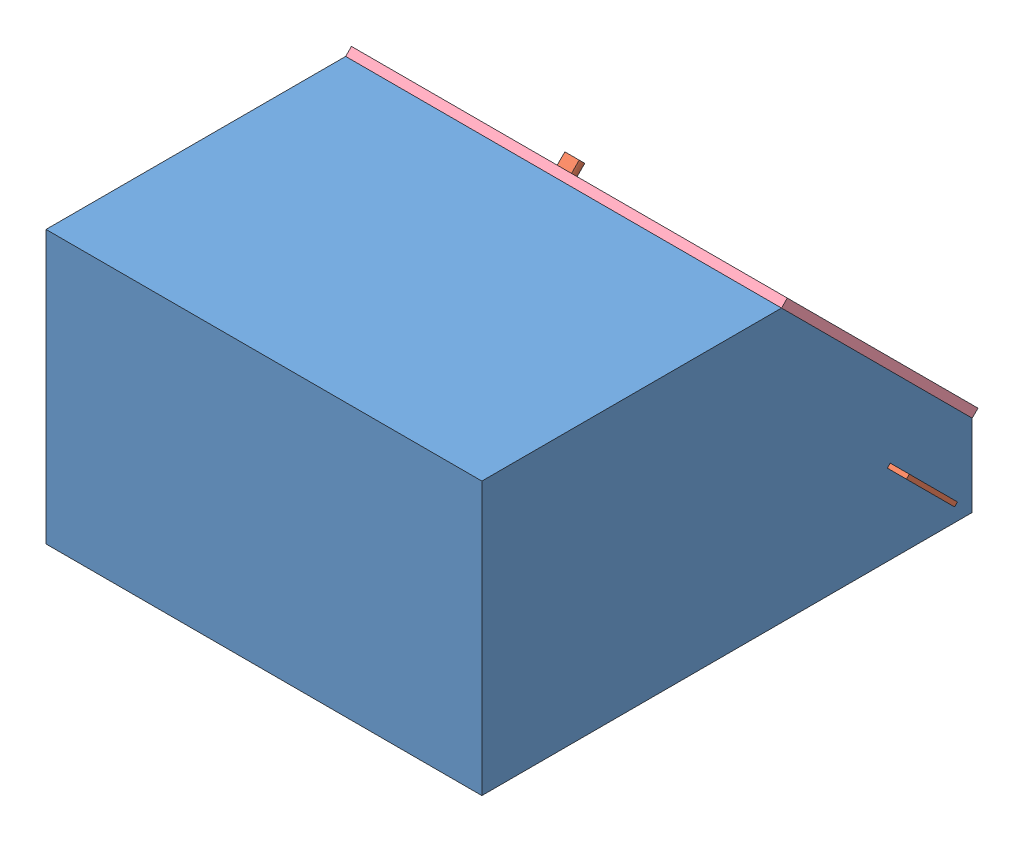
SolidWorks assembly Electronics Box, configuration Default. Lengths in mm.
Overall size (167 103.37 199.93).
8 component instances, 7 part files, 16 mates.
Components (placement in the parent):
- Enclosure Base-1: Enclosure Base [Default] at (0 103 -802.3521) x (0 0 1) z (1 0 0) size (180 100 160)
- lcd-1: lcd [Default] at (-153 49.1312 -757.9367) x (1 0 0) z (0 0.707107 0.707107) size (160 30 64)
- Makerbase-1: Makerbase [Default] at (-100 94.4 -667.3521) x (1 0 0) z (0 0 -1) size (110 22.06 84)
- PC FAN-1: PC FAN [Default] at (-64 15.5 -695.3521) x (-1 0 0) z (0 1 0) size (183.81 183.8 33.39) (hidden)
  - CPU Fan with no fan-1: CPU Fan with no fan [Default] at origin size (120 120 33.39)
  - Part3^PC FAN-1: Part3^PC FAN [Default] at (0 0 -9.5) x (-0.828072 -0.560621 0) z (0 0 1) size (132.38 132.34 22) (virtual)
- Enclosure Bottom-1: Enclosure Bottom [Default] at (0 3 -802.3521) x (0 0 1) z (1 0 0) size (250 3 128) (hidden)
- LCD Mount 2 Lines-1: LCD Mount 2 Lines [Default] at (0 33 -802.3521) x (-1 0 0) z (0 -0.707107 -0.707107) size (160 3 99)
Mates (geometry in assembly coordinates):
- Distance1: distance = 4 mm anti-aligned: plane of Makerbase-1 through (-100 96 -667.3521) normal (0 1 0); plane of Enclosure Base-1 through (0 100 -802.3521) normal (0 -1 0)
- Distance3: distance = 1 mm anti-aligned: plane of PC FAN-1/CPU Fan with no fan-1 through (-4 28 -750.8521) normal (1 0 0); plane of Enclosure Base-1 through (-3 3 -625.3521) normal (-1 0 0)
- Distance4: distance = 10 mm anti-aligned: plane of PC FAN-1/CPU Fan with no fan-1 through (-8.5 28 -635.3521) normal (0 0 1); plane of Enclosure Base-1 through (-3 3 -625.3521) normal (0 0 -1)
- Coincident6: coincident aligned: plane of Enclosure Base-1 through (0 3 -802.3521) normal (0 -1 0); plane of PC FAN-1/CPU Fan with no fan-1 through (-8.5 3 -750.8521) normal (0 -1 0)
- Distance5: distance = 2 mm anti-aligned: plane of Enclosure Base-1 through (-157 3 -625.3521) normal (1 0 0); plane of Makerbase-1 through (-155 96 -709.3521) normal (-1 0 0)
- Coincident9: coincident anti-aligned: plane of Enclosure Base-1 through (-3 3 -625.3521) normal (0 0 -1); plane of Makerbase-1 through (-155 96 -625.3521) normal (0 0 1)
- Coincident14: coincident aligned: plane of Enclosure Base-1 through (0 100 -802.3521) normal (0 0 -1); plane of Enclosure Bottom-1 through (0 0 -802.3521) normal (0 0 -1)
- Coincident15: coincident aligned: plane of Enclosure Base-1 through (0 100 -802.3521) normal (1 0 0); plane of Enclosure Bottom-1 through (0 0 -802.3521) normal (1 0 0)
- Coincident16: coincident anti-aligned: plane of Enclosure Base-1 through (0 3 -802.3521) normal (0 -1 0); plane of Enclosure Bottom-1 through (0 3 -802.3521) normal (0 1 0)
- Coincident21: coincident aligned: plane of Enclosure Base-1 through (0 100 -802.3521) normal (1 0 0); plane of LCD Mount 2 Lines-1 through (0 35.1213 -804.4734) normal (1 0 0)
- Coincident22: coincident anti-aligned: line of Enclosure Base-1 through (-160 33 -802.3521) axis (1 0 0); line of LCD Mount 2 Lines-1 through (0 33 -802.3521) axis (-1 0 0)
- Coincident23: coincident anti-aligned: plane of Enclosure Base-1 through (-160 33 -802.3521) normal (0 0.707107 -0.707107); plane of LCD Mount 2 Lines-1 through (0 33 -802.3521) normal (0 -0.707107 0.707107)
- Coincident24: coincident anti-aligned: plane of Enclosure Bottom-1 through (0 0 -802.3521) normal (0 -1 0)
- Coincident25: coincident aligned: plane of Enclosure Base-1 through (0 100 -802.3521) normal (1 0 0)
- Coincident26: coincident anti-aligned: plane of lcd-1 through (-115 53.3738 -781.9783) normal (0 0.707107 -0.707107); plane of LCD Mount 2 Lines-1 through (0 33 -802.3521) normal (0 -0.707107 0.707107)
- Coincident27: coincident anti-aligned: plane of Enclosure Base-1 through (-3 3 -625.3521) normal (-1 0 0); plane of lcd-1 through (-3 50.5454 -759.3509) normal (1 0 0)
